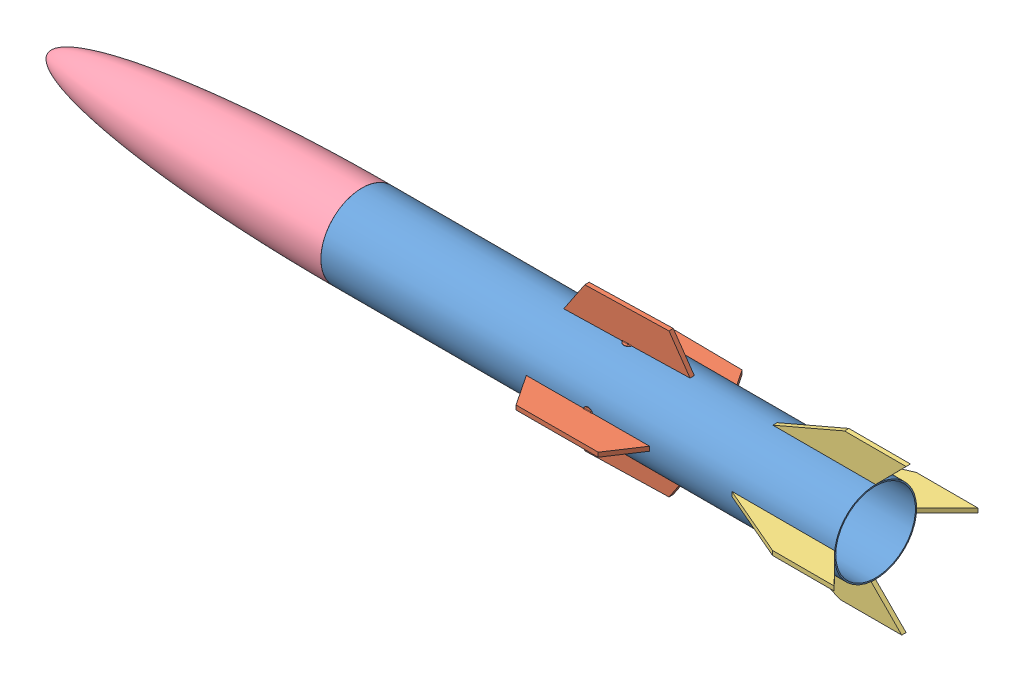
SolidWorks assembly CoheteGUI, configuration Predeterminado. Lengths in mm.
Overall size (834.7 140 140).
10 component instances, 4 part files, 13 mates.
Components (placement in the parent):
- Cuerpo-1: Cuerpo [Predeterminado] at (-151.2093 -26.6482 1000) size (500 80 80)
- Aletas-Moviles-1: Aletas-Moviles [Predeterminado] at (-141.2093 -26.6482 1040) x (0.999997 0.002629 0) z (0.002629 -0.999997 0) size (120 32.5 10)
- Aletas-Moviles-2: Aletas-Moviles [Predeterminado] at (-141.2093 -66.6482 1000) x (-0.99967 0 0.025699) z (0.025699 0 0.99967) size (120 32.5 10)
- Aletas-Moviles-3: Aletas-Moviles [Predeterminado] at (-141.2093 -26.6482 960) x (-0.999923 0.012434 0) z (-0.012434 -0.999923 0) size (120 32.5 10)
- Aletas-Moviles-4: Aletas-Moviles [Predeterminado] at (-141.2093 13.3518 1000) x (-0.999687 0 0.025006) z (-0.025006 0 -0.999687) size (120 32.5 10)
- Aletas-Fijas-1: Aletas-Fijas [Predeterminado] at (-1.2093 13.3518 997.875) size (129.7 30 4.25)
- Ojiva-1: Ojiva [Predeterminado] at (-401.2093 -26.6482 1000) x (0 1 0) z (0 0 1) size (80 305 80)
- Aletas-Fijas-2: Aletas-Fijas [Predeterminado] at (-1.2093 -24.5232 1040) x (1 0 0) z (0 -1 0) size (129.7 30 4.25)
- Aletas-Fijas-3: Aletas-Fijas [Predeterminado] at (-1.2093 -66.6482 1002.125) x (1 0 0) z (0 0 -1) size (129.7 30 4.25)
- Aletas-Fijas-4: Aletas-Fijas [Predeterminado] at (-1.2093 -28.7732 960) x (1 0 0) z (0 1 0) size (129.7 30 4.25)
Mates (geometry in assembly coordinates):
- Concéntrica1: concentric anti-aligned: cylinder of Cuerpo-1 through (-141.2093 13.3518 1000) axis (0 -1 0) radius 5; cylinder of Aletas-Moviles-4 through (-141.2093 10.8518 1000) axis (0 1 0) radius 5
- Concéntrica2: concentric aligned: cylinder of Cuerpo-1 through (-141.2093 -26.6482 960) axis (0 0 1) radius 5; cylinder of Aletas-Moviles-1 through (-141.2093 -26.6482 1037.5) axis (0 0 1) radius 5
- Concéntrica3: concentric anti-aligned: cylinder of Cuerpo-1 through (-141.2093 -26.6482 960) axis (0 0 1) radius 5; cylinder of Aletas-Moviles-3 through (-141.2093 -26.6482 962.5) axis (0 0 -1) radius 5
- Concéntrica4: concentric aligned: cylinder of Cuerpo-1 through (-141.2093 -26.6482 960) axis (0 0 1) radius 5; cylinder of Aletas-Moviles-1 through (-141.2093 -26.6482 1037.5) axis (0 0 1) radius 5
- Concéntrica5: concentric aligned: cylinder of Cuerpo-1 through (-141.2093 13.3518 1000) axis (0 -1 0) radius 5; cylinder of Aletas-Moviles-2 through (-141.2093 -64.1482 1000) axis (0 -1 0) radius 5
- Tangente1: tangent anti-aligned: cylinder of Cuerpo-1 through (98.7907 -26.6482 1000) axis (-1 0 0) radius 40; plane of Aletas-Fijas-1 through (-1.2093 13.3518 1000) normal (0 -1 0)
- Coincidente1: coincident: circle of Cuerpo-1; point of Aletas-Fijas-1
- Tangente2: tangent anti-aligned: cylinder of Cuerpo-1 through (98.7907 -26.6482 1000) axis (-1 0 0) radius 40; plane of Aletas-Moviles-4 through (-201.2437 13.3518 999.376) normal (0 -1 0)
- Tangente3: tangent anti-aligned: cylinder of Cuerpo-1 through (98.7907 -26.6482 1000) axis (-1 0 0) radius 40; plane of Aletas-Moviles-3 through (-201.2311 -28.0271 960) normal (0 0 1)
- Tangente4: tangent anti-aligned: cylinder of Cuerpo-1 through (98.7907 -26.6482 1000) axis (-1 0 0) radius 40; plane of Aletas-Moviles-2 through (-201.1349 -66.6482 1003.6663) normal (0 1 0)
- Tangente5: tangent anti-aligned: cylinder of Cuerpo-1 through (98.7907 -26.6482 1000) axis (-1 0 0) radius 40; plane of Aletas-Moviles-1 through (-81.204 -28.6155 1040) normal (0 0 -1)
- Coincidente2: coincident anti-aligned: plane of Cuerpo-1 through (-401.2093 -26.6482 1000) normal (-1 0 0); plane of Ojiva-1 through (-401.2093 -26.6482 1000) normal (1 0 0)
- Tangente7: tangent aligned: cylinder of Cuerpo-1 through (98.7907 -26.6482 1000) axis (-1 0 0) radius 40; face of Ojiva-1
